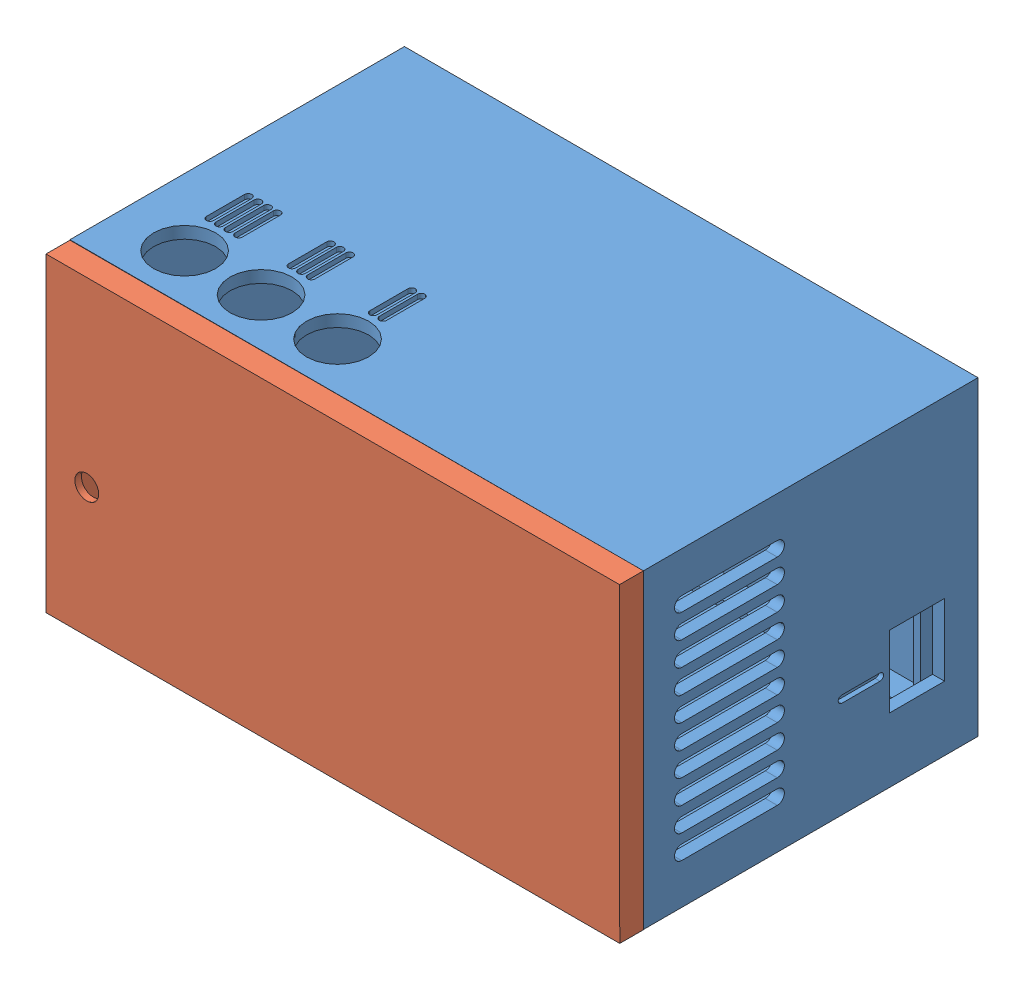
SolidWorks assembly Assem3, configuration Default. Lengths in mm.
Overall size (120.05 65.09 75).
2 component instances, 2 part files, 2 mates.
Components (placement in the parent):
- box-1: box [Default] at origin size (120 65 70)
- cover-1: cover [Default] at (0 64.9144 72.5) x (1 0.000713 0) z (0 0 -1) size (120 65 7.5)
Mates (geometry in assembly coordinates):
- Coincident7: coincident: plane of box-1 through (0 0 70) normal (0 0 1); plane of cover-1 through (0 64.9144 70) normal (0 0 -1)
- Coincident8: coincident: point of box-1; point of cover-1
